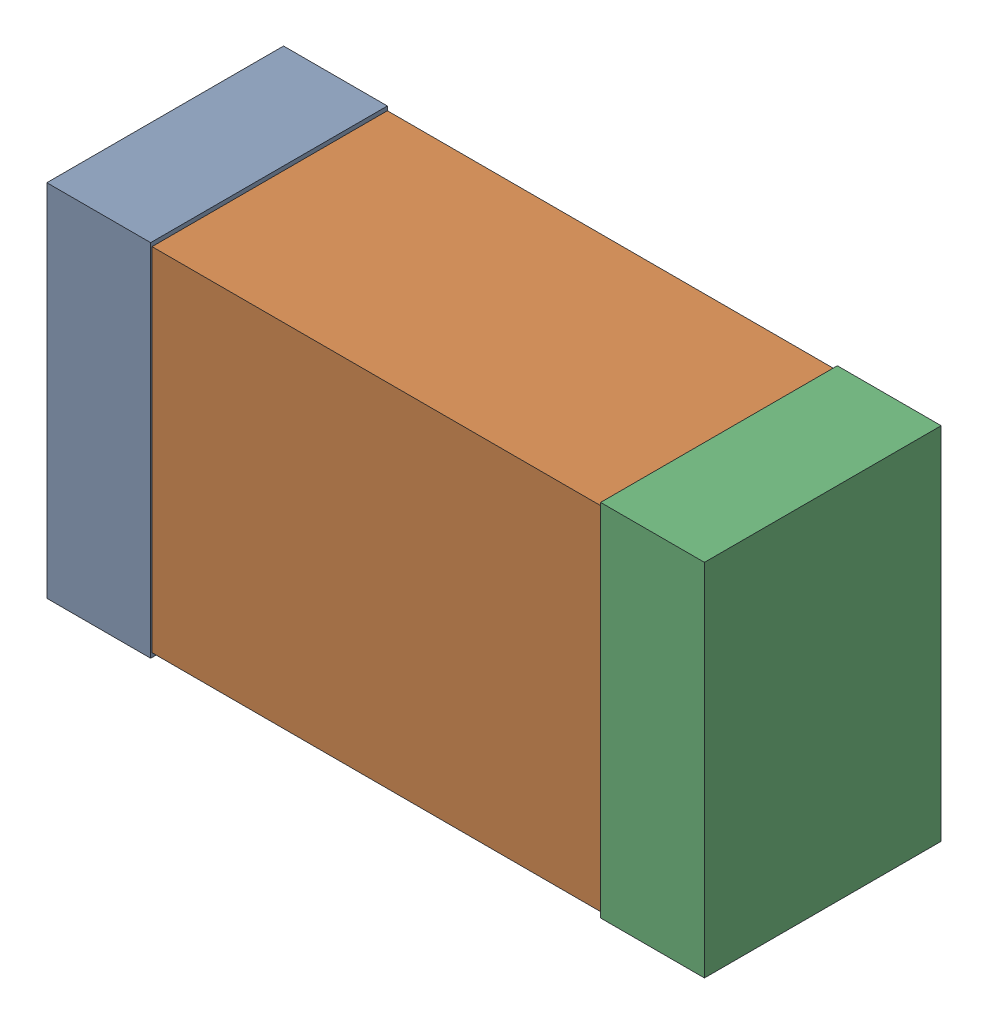
SolidWorks assembly C14_Motor_5Kanaloa_v2.0.0_Motor, configuration Default. Lengths in mm.
Overall size (2.38 1.3 0.85).
6 component instances, 2 part files, 0 mates.
Components (placement in the parent):
- 352877648-1: 352877648 [Default] at (119.353 83.82 0) size (0.38 1.3 0.85)
  - Extruded_14-1: Extruded_14 [Default] at origin size (0.38 1.3 0.85)
- 352877392-1: 352877392 [Default] at (120.353 83.82 0) size (2.2 1.27 0.85)
  - Extruded_15-1: Extruded_15 [Default] at origin size (2.2 1.27 0.85)
- 352877648-2: 352877648 [Default] at (121.353 83.82 0) size (0.38 1.3 0.85)
  - Extruded_14-1: Extruded_14 [Default] at origin size (0.38 1.3 0.85)
